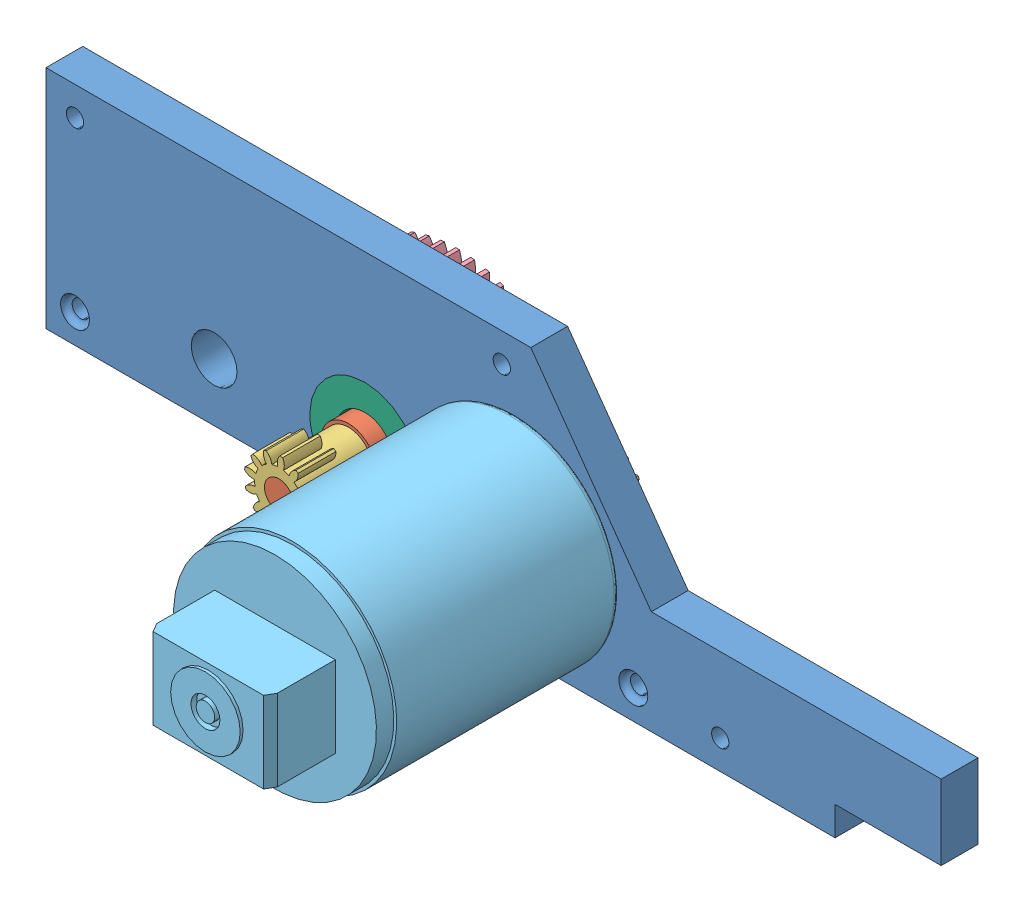
SolidWorks assembly MotorMountDerechoAlvaro, configuration Predeterminado. Lengths in mm.
Overall size (154.41 54 69.5).
9 component instances, 6 part files, 7 mates.
Components (placement in the parent):
- B_Motor_Derecha_Alvaro-1: B_Motor_Derecha_Alvaro [Predeterminado] at (43.0754 -12.0207 159.3322) x (-1 0 0) z (0 0 -1) size (154.41 47 6.35)
- CopleEngrane-1: CopleEngrane [Predeterminado] at (-61.2505 -9.4005 154.3995) x (0 0 -1) z (0.984779 0.173814 0) size (30.68 43.16 43.16)
  - Cople-1: Cople [Predeterminado] at (4.4173 -10.5202 49.0087) x (0 0 -1) z (0 -1 0) size (34.5 28.68 34.5)
  - Gear 13T-1: Gear 13T [Default] at (-13.2577 -10.5202 49.0087) x (-1 0 0) z (0 0 -1) size (12 11.88 11.96)
  - Gear_52T-1: Gear_52T [Predeterminado] at (4.4173 -10.5202 49.0087) size (6.5 43.16 43.16)
- MotorEngrane-1: MotorEngrane [Predeterminado] at (19.9901 -79.5422 177.3161) x (1 0 0) z (0 1 0) size (36 69.5 36)
  - Motor-1: Motor [Default] at (-5.1493 -20.5161 68.3) size (36 68.3 36)
  - Gear 13T-1: Gear 13T [Default] at (-5.1493 27.4839 68.3) x (0 1 0) z (-0.927124 0 -0.374755) size (12 11.88 11.96)
- valero-1: valero [Predeterminado] at (-11.1592 -11.2422 154.3322) x (0.98096 -0.194212 0) z (0 0 1) size (19 19 5)
Mates (geometry in assembly coordinates):
- Concéntrica3: concentric: cylinder of B_Motor_Derecha_Alvaro-1 through (-11.1592 -11.2422 154.3322) axis (0 0 1) radius 11; cylinder of valero-1 through (-11.1592 -11.2422 159.3322) axis (0 0 -1) radius 9.5
- Coincidente3: coincident: plane of B_Motor_Derecha_Alvaro-1 through (-11.1592 -11.2422 154.3322) normal (0 0 1); plane of valero-1 through (-11.1592 -11.2422 154.3322) normal (0 0 -1)
- Concéntrica4: concentric: cylinder of B_Motor_Derecha_Alvaro-1 through (-11.1592 -11.2422 152.9812) axis (0 0 1) radius 4; cylinder of CopleEngrane-1/Cople-1 through (-11.1592 -11.2422 162.1572) axis (0 0 -1) radius 4.75
- Coincidente4: coincident: plane of B_Motor_Derecha_Alvaro-1 through (43.0754 -12.0207 152.9822) normal (0 0 -1); plane of CopleEngrane-1/Cople-1 through (-11.1592 -11.2422 152.9822) normal (0 0 1)
- Concéntrica5: concentric: cylinder of B_Motor_Derecha_Alvaro-1 through (14.8408 -11.2422 152.9822) axis (0 0 1) radius 7.5; cylinder of MotorEngrane-1/Motor-1 through (14.8408 -11.2422 155.3322) axis (0 0 1) radius 5.1
- Paralelo1: parallel: plane of B_Motor_Derecha_Alvaro-1 through (-66.1592 17.7578 152.9822) normal (0 1 0); plane of MotorEngrane-1/Motor-1 through (-11.551 -4.2422 200.8322) normal (0 1 0)
- Coincidente6: coincident: plane of B_Motor_Derecha_Alvaro-1 through (43.0754 -12.0207 159.3322) normal (0 0 1); plane of MotorEngrane-1/Motor-1 through (14.8408 -11.2422 159.3322) normal (0 0 -1)
